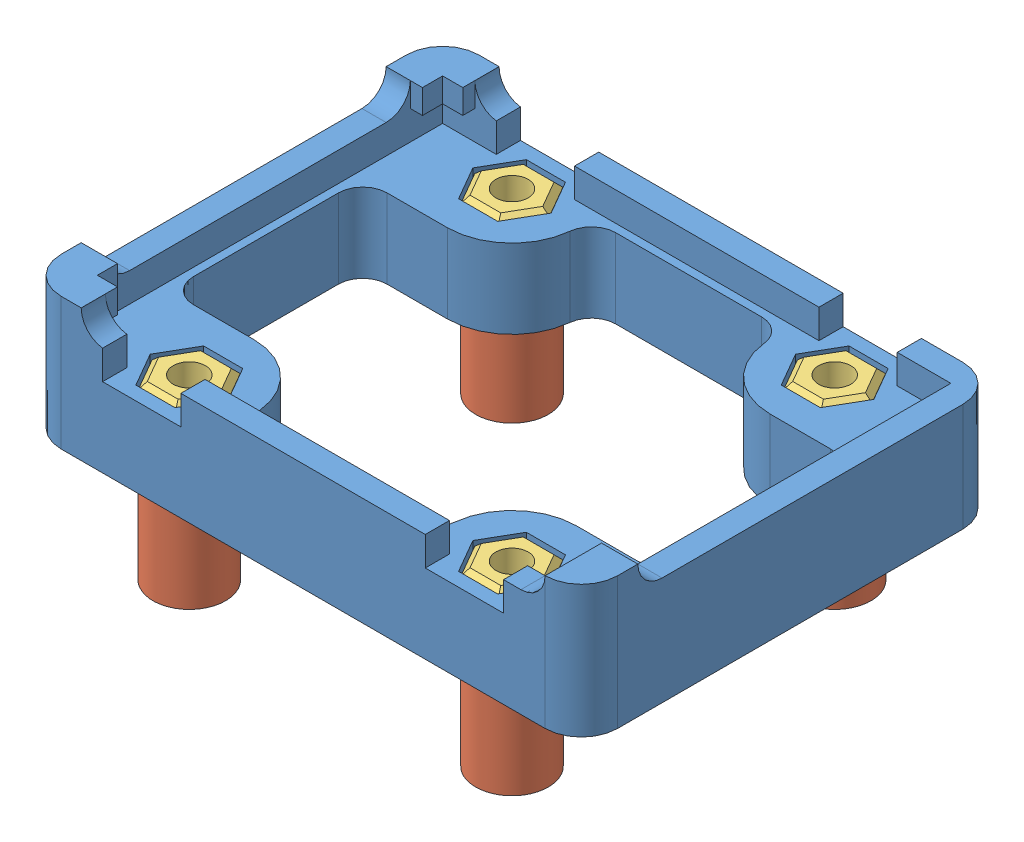
SolidWorks assembly vtx-mount, configuration Default. Lengths in mm.
Overall size (34.5 14.2 26.09).
9 component instances, 3 part files, 20 mates.
Components (placement in the parent):
- vtx-mount-1: vtx-mount [Default] at origin size (34.5 8.2 25.9)
- rubber-grommet-1: rubber-grommet [Default] at (-10 -6 10) x (0.807632 0 0.589687) z (-0.589687 0 0.807632) size (4.5 9 4.5)
- rubber-grommet-2: rubber-grommet [Default] at (10 -6 10) x (0.90429 0 0.426919) z (-0.426919 0 0.90429) size (4.5 9 4.5)
- rubber-grommet-3: rubber-grommet [Default] at (-10 -6 -10) x (0.97506 0 0.22194) z (-0.22194 0 0.97506) size (4.5 9 4.5)
- rubber-grommet-4: rubber-grommet [Default] at (10 -6 -10) x (0.999918 0 -0.01283) z (0.01283 0 0.999918) size (4.5 9 4.5)
- nut-m2-1: nut-m2 [Default] at (-10 5 10) x (1 0 0) z (0 -1 0) size (4.62 4 2)
- nut-m2-2: nut-m2 [Default] at (-10 5 -10) x (1 0 0) z (0 -1 0) size (4.62 4 2)
- nut-m2-4: nut-m2 [Default] at (10 5 -10) x (1 0 0) z (0 -1 0) size (4.62 4 2)
- nut-m2-6: nut-m2 [Default] at (10 5 10) x (1 0 0) z (0 -1 0) size (4.62 4 2)
Mates (geometry in assembly coordinates):
- Concentric1: concentric aligned: cylinder of vtx-mount-1 through (-10 1.5 10) axis (0 -1 0) radius 1.55; cylinder of rubber-grommet-1 through (-10 0 10) axis (0 -1 0) radius 1
- Coincident1: coincident anti-aligned: plane of vtx-mount-1 through (0 0 0) normal (0 -1 0); plane of rubber-grommet-1 through (-10 0 10) normal (0 1 0)
- Coincident2: coincident anti-aligned: plane of vtx-mount-1 through (0 0 0) normal (0 -1 0); plane of rubber-grommet-2 through (10 0 10) normal (0 1 0)
- Concentric2: concentric aligned: cylinder of vtx-mount-1 through (10 1.5 10) axis (0 -1 0) radius 1.55; cylinder of rubber-grommet-2 through (10 0 10) axis (0 -1 0) radius 1
- Coincident3: coincident anti-aligned: plane of vtx-mount-1 through (0 0 0) normal (0 -1 0); plane of rubber-grommet-3 through (-10 0 -10) normal (0 1 0)
- Concentric3: concentric aligned: cylinder of vtx-mount-1 through (-10 1.5 -10) axis (0 -1 0) radius 1.55; cylinder of rubber-grommet-3 through (-10 0 -10) axis (0 -1 0) radius 1
- Coincident4: coincident anti-aligned: plane of vtx-mount-1 through (0 0 0) normal (0 -1 0); plane of rubber-grommet-4 through (10 0 -10) normal (0 1 0)
- Concentric4: concentric aligned: cylinder of vtx-mount-1 through (10 1.5 -10) axis (0 -1 0) radius 1.55; cylinder of rubber-grommet-4 through (10 0 -10) axis (0 -1 0) radius 1
- Concentric5: concentric anti-aligned: cylinder of rubber-grommet-1 through (-10 0 10) axis (0 -1 0) radius 1; cylinder of nut-m2-1 through (-10 3 10) axis (0 1 0) radius 1
- Coincident6: coincident anti-aligned: plane of rubber-grommet-1 through (-10 3 10) normal (0 1 0); plane of nut-m2-1 through (-10 3 10) normal (0 -1 0)
- Parallel1: parallel anti-aligned: plane of vtx-mount-1 through (-4.9885 4.9 -2.8801) normal (0.866025 0 0.5); plane of nut-m2-1 through (-12.3094 3 10) normal (-0.866025 0 -0.5)
- Concentric6: concentric anti-aligned: cylinder of rubber-grommet-3 through (-10 0 -10) axis (0 -1 0) radius 1; cylinder of nut-m2-2 through (-10 3 -10) axis (0 1 0) radius 1
- Coincident8: coincident anti-aligned: plane of rubber-grommet-3 through (-10 3 -10) normal (0 1 0); plane of nut-m2-2 through (-10 3 -10) normal (0 -1 0)
- Parallel2: parallel anti-aligned: plane of vtx-mount-1 through (-13.6488 4.9 -7.8801) normal (0.866025 0 0.5); plane of nut-m2-2 through (-12.3094 3 -10) normal (-0.866025 0 -0.5)
- Concentric7: concentric anti-aligned: cylinder of rubber-grommet-4 through (10 0 -10) axis (0 -1 0) radius 1; cylinder of nut-m2-4 through (10 3 -10) axis (0 1 0) radius 1
- Coincident9: coincident anti-aligned: plane of rubber-grommet-4 through (10 3 -10) normal (0 1 0); plane of nut-m2-4 through (10 3 -10) normal (0 -1 0)
- Parallel3: parallel anti-aligned: plane of vtx-mount-1 through (1.3512 4.9 0.7801) normal (0.866025 0 0.5); plane of nut-m2-4 through (7.6906 3 -10) normal (-0.866025 0 -0.5)
- Concentric8: concentric anti-aligned: cylinder of rubber-grommet-2 through (10 0 10) axis (0 -1 0) radius 1; cylinder of nut-m2-6 through (10 3 10) axis (0 1 0) radius 1
- Coincident10: coincident anti-aligned: plane of rubber-grommet-2 through (10 3 10) normal (0 1 0); plane of nut-m2-6 through (10 3 10) normal (0 -1 0)
- Parallel4: parallel anti-aligned: plane of vtx-mount-1 through (10.0115 4.9 5.7801) normal (0.866025 0 0.5); plane of nut-m2-6 through (7.6906 3 10) normal (-0.866025 0 -0.5)
